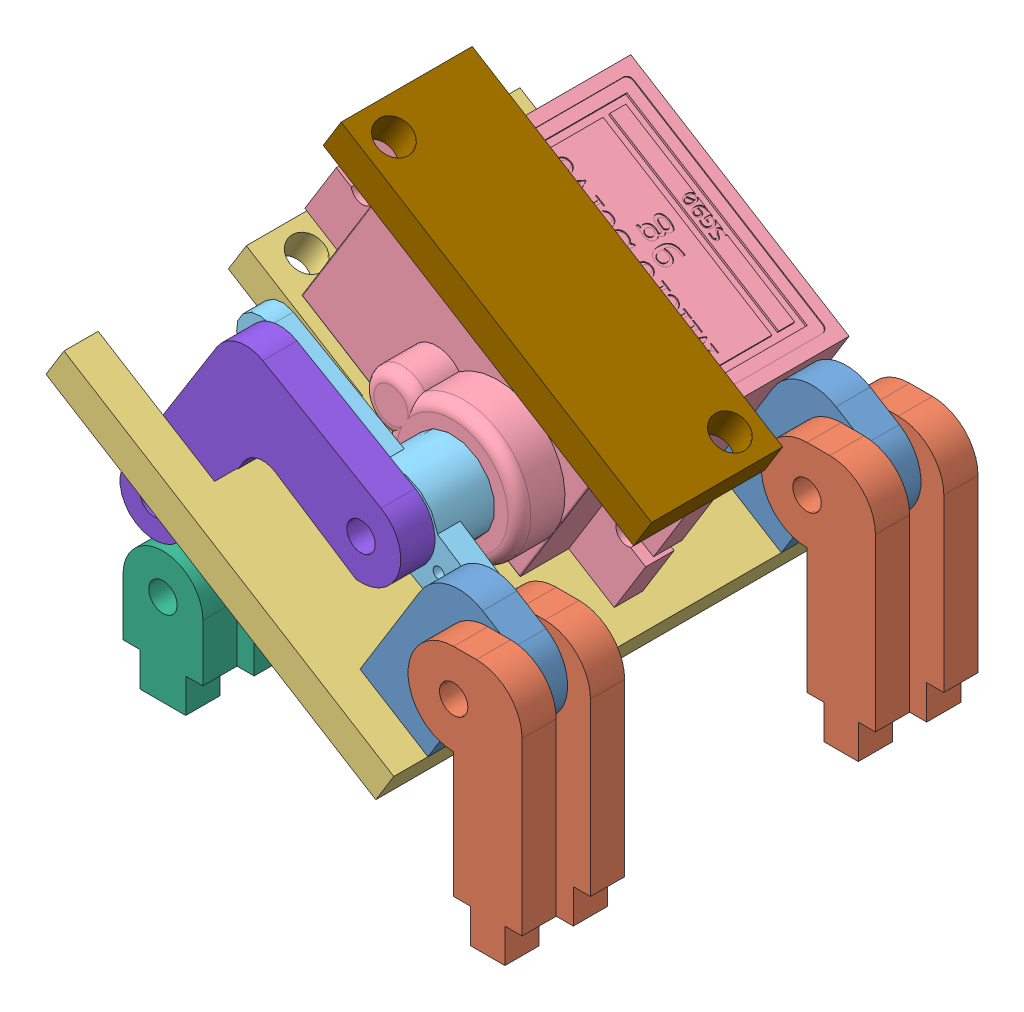
SolidWorks assembly Magnet release assembly, configuration Default. Lengths in mm.
Overall size (42.68 40.1 40).
14 component instances, 9 part files, 39 mates.
Components (placement in the parent):
- bbq holder1-1: bbq holder1 [Default] at (5.8607 12.8935 9.2533) x (0.850932 -0.525275 0) z (0 0 1) size (11 17 3)
- bbq holder2-1: bbq holder2 [Default] at (5.8607 12.8935 6.2533) size (10 22 3)
- plate-1: plate [Default] at (-0.9679 1.8314 15.2533) x (0 0 -1) z (0.850932 -0.525275 0) size (40 3 34)
- bbq holder1-2: bbq holder1 [Default] at (5.8607 12.8935 -21.7467) x (0.850932 -0.525275 0) z (0 0 1) size (11 17 3)
- bbq holder2-2: bbq holder2 [Default] at (5.8607 12.8935 12.2533) size (10 22 3)
- Servo Motor (SG90)-1: Servo Motor (SG90) [Default] at (-11.8224 18.991 -13.0967) x (-0.850932 0.525275 0) z (0 0 -1) size (31.9 11.8 29.9)
- bbq holder2-3: bbq holder2 [Default] at (5.8607 12.8935 -18.7467) size (10 22 3)
- bbq holder2-4: bbq holder2 [Default] at (5.8607 12.8935 -24.7467) size (10 22 3)
- Microservo horn-1: Microservo horn [По умолчанию] at (-7.27 16.1807 7.2533) x (0.851204 -0.524834 0) z (0 0 -1) size (32 7.5 5)
- small hinge-1: small hinge [Default] at (-24.6393 2.8935 7.2533) size (7 11.5 3)
- link part-1: link part [Default] at (-25.4066 9.8513 4.2533) x (0.993974 0.109617 0) z (0 0 1) size (6 13 3)
- L part-1: L part [Default] at (-17.4352 22.5579 7.2533) x (0.984854 0.173388 0) z (0 0 1) size (25.46 17.21 3)
- small hinge-2: small hinge [Default] at (-24.6393 2.8935 1.2533) size (7 11.5 3)
- Servo mount-1: Servo mount [Default] at (4.8491 15.6333 -13.0467) x (-0.850932 0.525275 0) z (0 0 -1) size (32 3 11.5)
Mates (geometry in assembly coordinates):
- Coincident1: coincident anti-aligned: plane of bbq holder1-1 through (5.8607 12.8935 9.2533) normal (0 0 -1); plane of plate-1 through (-0.6684 5.1721 9.2533) normal (0 0 1)
- Coincident2: coincident anti-aligned: plane of bbq holder1-1 through (-4.0722 7.2732 12.2533) normal (-0.850932 0.525275 0); plane of plate-1 through (-4.0722 7.2732 12.2533) normal (0.850932 -0.525275 0)
- Coincident3: coincident aligned: plane of bbq holder1-1 through (-5.648 4.7204 12.2533) normal (-0.525275 -0.850932 0); plane of plate-1 through (-0.9679 1.8314 15.2533) normal (-0.525275 -0.850932 0)
- Coincident4: coincident anti-aligned: plane of plate-1 through (-4.0722 7.2732 -18.7467) normal (0 0 -1); plane of bbq holder1-2 through (5.8607 12.8935 -18.7467) normal (0 0 1)
- Coincident5: coincident anti-aligned: plane of plate-1 through (-4.0722 7.2732 -18.7467) normal (0.850932 -0.525275 0); plane of bbq holder1-2 through (-4.0722 7.2732 -18.7467) normal (-0.850932 0.525275 0)
- Coincident6: coincident aligned: plane of plate-1 through (-0.9679 1.8314 15.2533) normal (-0.525275 -0.850932 0); plane of bbq holder1-2 through (-5.648 4.7204 -18.7467) normal (-0.525275 -0.850932 0)
- Coincident7: coincident anti-aligned: plane of bbq holder1-1 through (5.8607 12.8935 9.2533) normal (0 0 -1); plane of bbq holder2-1 through (5.8607 12.8935 9.2533) normal (0 0 1)
- Coincident8: coincident anti-aligned: plane of bbq holder1-1 through (5.8607 12.8935 12.2533) normal (0 0 1); plane of bbq holder2-2 through (5.8607 12.8935 12.2533) normal (0 0 -1)
- Concentric1: concentric aligned: circle of bbq holder1-1; circle of bbq holder2-2
- Concentric3: concentric aligned: circle of bbq holder1-1; circle of bbq holder2-1
- Coincident12: coincident anti-aligned: plane of bbq holder1-2 through (5.8607 12.8935 -18.7467) normal (0 0 1); plane of bbq holder2-3 through (5.8607 12.8935 -18.7467) normal (0 0 -1)
- Concentric4: concentric aligned: circle of bbq holder1-2; circle of bbq holder2-3
- Coincident14: coincident anti-aligned: plane of bbq holder1-2 through (5.8607 12.8935 -21.7467) normal (0 0 -1); plane of bbq holder2-4 through (5.8607 12.8935 -21.7467) normal (0 0 1)
- Concentric5: concentric aligned: circle of bbq holder1-2; circle of bbq holder2-4
- Coincident16: coincident aligned: plane of bbq holder2-1 through (11.8607 16.8935 9.2533) normal (1 0 0); plane of bbq holder2-2 through (11.8607 16.8935 15.2533) normal (1 0 0)
- Coincident17: coincident aligned: plane of bbq holder2-3 through (11.8607 16.8935 -15.7467) normal (1 0 0); plane of bbq holder2-4 through (11.8607 16.8935 -21.7467) normal (1 0 0)
- Coincident18: coincident aligned: plane of bbq holder2-1 through (11.8607 16.8935 9.2533) normal (1 0 0); plane of bbq holder2-3 through (11.8607 16.8935 -15.7467) normal (1 0 0)
- Coincident19: coincident anti-aligned: plane of plate-1 through (0.6079 4.3842 15.2533) normal (0.525275 0.850932 0); plane of Servo Motor (SG90)-1 through (-14.9216 13.9705 -13.0967) normal (-0.525275 -0.850932 0)
- Parallel1: parallel aligned: plane of plate-1 through (0.6079 4.3842 -24.7467) normal (0 0 -1); plane of Servo Motor (SG90)-1 through (0.8497 18.1021 -24.4467) normal (0 0 -1)
- Coincident23: coincident anti-aligned: plane of Servo Motor (SG90)-1 through (-9.9504 17.8354 2.2533) normal (0 0 1); plane of Microservo horn-1 through (-7.27 16.1807 2.2533) normal (0 0 -1)
- Concentric6: concentric aligned: circle of Servo Motor (SG90)-1; circle of Microservo horn-1
- Coincident24: coincident anti-aligned: plane of bbq holder1-2 through (2.0053 19.9742 -18.7467) normal (-0.850932 0.525275 0); plane of Servo Motor (SG90)-1 through (0.8497 18.1021 -24.4467) normal (0.850932 -0.525275 0)
- Distance3: distance = 8 mm aligned: plane of Microservo horn-1 through (-7.27 16.1807 7.2533) normal (0 0 1); plane of plate-1 through (-28.3237 22.2436 -0.7467) normal (0 0 1)
- Distance4: distance = 2 mm anti-aligned: plane of small hinge-1 through (-24.6393 2.8935 10.2533) normal (0 0 1); plane of plate-1 through (-28.3237 22.2436 12.2533) normal (0 0 -1)
- Coincident29: coincident aligned: plane of bbq holder2-2 through (10.3607 -5.1065 15.2533) normal (0 -1 0); plane of small hinge-1 through (-26.6393 -5.1065 10.2533) normal (0 -1 0)
- Distance5: distance = 30 mm anti-aligned: plane of small hinge-1 through (-22.6393 -5.1065 10.2533) normal (1 0 0); plane of bbq holder2-2 through (7.3607 -5.1065 15.2533) normal (-1 0 0)
- Coincident31: coincident anti-aligned: plane of small hinge-1 through (-24.6393 2.8935 7.2533) normal (0 0 -1); plane of link part-1 through (-25.4066 9.8513 7.2533) normal (0 0 1)
- Concentric7: concentric aligned: circle of small hinge-1; circle of link part-1
- Coincident33: coincident anti-aligned: plane of Microservo horn-1 through (-7.27 16.1807 7.2533) normal (0 0 1); plane of L part-1 through (-7.27 16.1807 7.2533) normal (0 0 -1)
- Concentric9: concentric aligned: circle of Microservo horn-1; circle of L part-1
- Concentric11: concentric aligned: circle of link part-1; circle of L part-1
- Lock1: lock: unknown of Microservo horn-1; unknown of L part-1
- Parallel4: parallel anti-aligned: plane of link part-1 through (-25.4066 9.8513 7.2533) normal (0 0 1); plane of L part-1 through (-7.27 16.1807 7.2533) normal (0 0 -1)
- Coincident39: coincident anti-aligned: plane of link part-1 through (-25.4066 9.8513 4.2533) normal (0 0 -1); plane of small hinge-2 through (-24.6393 2.8935 4.2533) normal (0 0 1)
- Coincident40: coincident aligned: plane of small hinge-1 through (-26.6393 -2.1065 10.2533) normal (-1 0 0); plane of small hinge-2 through (-26.6393 -2.1065 4.2533) normal (-1 0 0)
- Concentric12: concentric aligned: circle of link part-1; circle of small hinge-2
- Coincident50: coincident anti-aligned: plane of Servo Motor (SG90)-1 through (-8.7233 24.0115 -13.0967) normal (0.525275 0.850932 0); plane of Servo mount-1 through (4.8491 15.6333 -13.0467) normal (-0.525275 -0.850932 0)
- Coincident52: coincident aligned: plane of Servo Motor (SG90)-1 through (1.7499 10.6128 -13.0967) normal (0.850932 -0.525275 0); plane of Servo mount-1 through (6.4249 18.1861 -13.0467) normal (0.850932 -0.525275 0)
- Distance15: distance = 0.5 mm anti-aligned: plane of Servo Motor (SG90)-1 through (-1.3492 5.5923 -8.5467) normal (0 0 -1); cylinder of Servo mount-1 through (4.2976 19.4993 -10.5467) axis (-0.525275 -0.850932 0) radius 1.5
